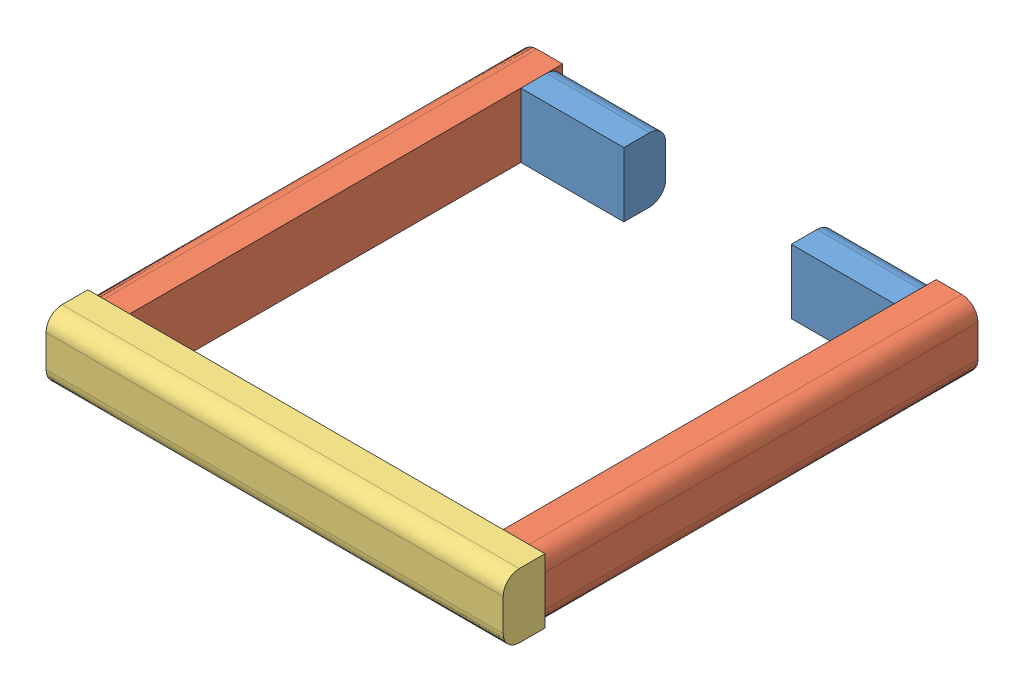
SolidWorks assembly Bumpers, configuration Default. Lengths in mm.
Overall size (901.7 127 936.5).
5 component instances, 3 part files, 15 mates.
Components (placement in the parent):
- Bumper 8in-1: Bumper 8in [Default] at (-266.7 0 -387.1254) size (203.2 127 82.55)
- Bumper 8in-2: Bumper 8in [Default] at (266.7 0 -387.1254) size (203.2 127 82.55)
- Bumper 33.62in-1: Bumper 33.62in [Default] at (369.7264 0 -41.275) x (0 0 1) z (-1 0 0) size (853.95 127 82.55)
- Bumper 33.62in-2: Bumper 33.62in [Default] at (-369.7264 0 -41.275) x (0 0 -1) z (1 0 0) size (853.95 127 82.55)
- Bumper 35.5in-1: Bumper 35.5in [Default] at (0 0 387.1254) x (-1 0 0) z (0 0 -1) size (901.7 127 82.55)
Mates (geometry in assembly coordinates):
- Coincident1: coincident aligned: plane of Bumper 8in-1 through (-266.7 0 -387.1254) normal (0 1 0); plane of assembly through (0 0 0) normal (0 1 0)
- Coincident2: coincident aligned: plane of Bumper 8in-2 through (266.7 0 -387.1254) normal (0 1 0); plane of assembly through (0 0 0) normal (0 1 0)
- Coincident3: coincident aligned: plane of Bumper 33.62in-1; plane of assembly through (0 0 0) normal (0 1 0)
- Coincident4: coincident aligned: plane of Bumper 35.5in-1; plane of assembly through (0 0 0) normal (0 1 0)
- Coincident5: coincident aligned: plane of Bumper 33.62in-2; plane of assembly through (0 0 0) normal (0 1 0)
- Coincident9: coincident aligned: plane of Bumper 8in-2 through (368.3 34.2717 -468.249) normal (0 0 -1); plane of Bumper 33.62in-1 through (419.1 -29.2283 -468.249) normal (0 0 -1)
- Coincident10: coincident aligned: plane of Bumper 8in-1 through (-165.1 34.2717 -468.249) normal (0 0 -1); plane of Bumper 33.62in-2 through (-419.1 -29.2283 -468.249) normal (0 0 -1)
- Coincident11: coincident aligned: plane of Bumper 33.62in-1 through (450.85 34.2717 385.699) normal (1 0 0); plane of Bumper 35.5in-1 through (450.85 -29.2283 436.499) normal (1 0 0)
- Coincident12: coincident aligned: plane of Bumper 33.62in-2 through (-450.85 34.2717 -468.249) normal (-1 0 0); plane of Bumper 35.5in-1 through (-450.85 -29.2283 436.499) normal (-1 0 0)
- Coincident13: coincident anti-aligned: plane of Bumper 35.5in-1 through (0 0 387.1254) normal (-1 0 0); plane of assembly through (0 0 0) normal (1 0 0)
- Coincident14: coincident anti-aligned: plane of Bumper 8in-1 through (-368.3 -29.2283 -436.499) normal (-1 0 0); plane of Bumper 33.62in-2 through (-368.3 66.0217 -468.249) normal (1 0 0)
- Coincident15: coincident anti-aligned: plane of Bumper 8in-2 through (368.3 -29.2283 -436.499) normal (1 0 0); plane of Bumper 33.62in-1 through (368.3 66.0217 385.699) normal (-1 0 0)
- Coincident16: coincident anti-aligned: plane of Bumper 33.62in-1 through (419.1 -29.2283 385.699) normal (0 0 1); plane of Bumper 35.5in-1 through (-450.85 66.0217 385.699) normal (0 0 -1)
- Coincident17: coincident anti-aligned: plane of Bumper 33.62in-2 through (-419.1 -29.2283 385.699) normal (0 0 1); plane of Bumper 35.5in-1 through (-450.85 66.0217 385.699) normal (0 0 -1)
- Distance1: distance = 41.275 mm anti-aligned: plane of Bumper 33.62in-2 through (-369.7264 0 -41.275) normal (0 0 -1); plane of assembly through (0 0 0) normal (0 0 1)
